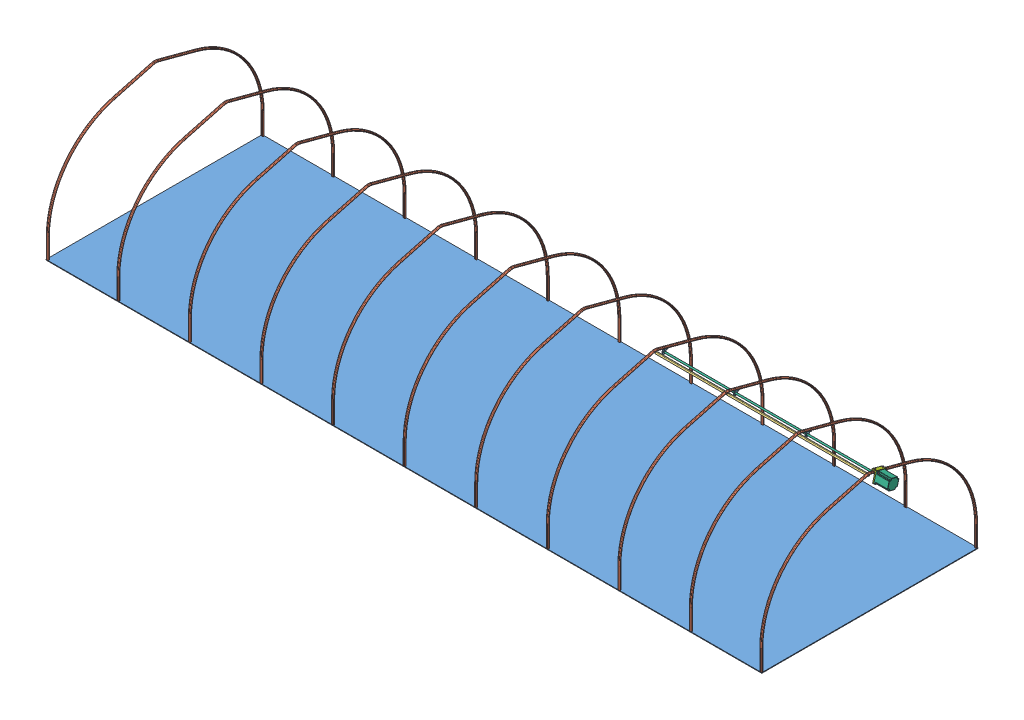
SolidWorks assembly Greenhouse_skrt, configuration Default. Lengths in mm.
Overall size (31100.8 5099.94 9207.5).
34 component instances, 7 part files, 68 mates.
Components (placement in the parent):
- Base 2-1: Base 2 [Default] at (10136.1399 15684.6804 24201.437) size (30480 25.4 9207.5)
- Arch-1: Arch [Default] at (25306.3916 15710.0804 28773.437) size (101.4 5043.5 9207.5)
- Arch-2: Arch [Default] at (22309.0899 15710.0801 28773.437) x (1 0.000015 0) z (0 0 1) size (101.4 5043.5 9207.5)
- Arch-3: Arch [Default] at (19261.0899 15710.0804 28773.437) size (101.4 5043.5 9207.5)
- Arch-8: Arch [Default] at (16213.0899 15710.0804 28773.437) size (101.4 5043.5 9207.5)
- Arch-10: Arch [Default] at (13165.0899 15710.0804 28773.437) size (101.4 5043.5 9207.5)
- Arch-11: Arch [Default] at (10117.0899 15710.0804 28773.437) size (101.4 5043.5 9207.5)
- Arch-12: Arch [Default] at (7069.0899 15710.0804 28773.437) size (101.4 5043.5 9207.5)
- Arch-13: Arch [Default] at (4021.0899 15710.0804 28773.437) size (101.4 5043.5 9207.5)
- Arch-14: Arch [Default] at (973.0899 15710.0804 28773.437) size (101.4 5043.5 9207.5)
- Arch-15: Arch [Default] at (-2074.9101 15710.0804 28773.437) size (101.4 5043.5 9207.5)
- Arch-16: Arch [Default] at (-5072.2119 15710.0804 28773.437) size (101.4 5043.5 9207.5)
- Beam-3: Beam [Default] at (25325.2675 20658.2948 24182.387) x (0 0 1) z (0.000015 -1 0) size (101.6 2997.2 63.5)
- heavy hex bolt_ai-9: heavy hex bolt_ai [HHBOLT 0.5000-20x0.5x0.5-N] at (25306.2173 20669.3537 24182.387) x (-0.000015 1 0) z (0 0 1) size (21.95 25.66 22.23)
- heavy hex bolt_ai-10: heavy hex bolt_ai [HHBOLT 0.5000-20x0.5x0.5-N] at (25306.2173 20669.3537 24220.487) x (-0.000015 1 0) z (0 0 1) size (21.95 25.66 22.23)
- heavy hex bolt_ai-12: heavy hex bolt_ai [HHBOLT 0.5000-20x0.5x0.5-N] at (25344.3899 20680.8325 24182.387) x (0 1 0) z (0 0 1) size (21.95 25.66 22.23)
- heavy hex bolt_ai-14: heavy hex bolt_ai [HHBOLT 0.5000-20x0.5x0.5-N] at (25344.3899 20680.8325 24220.487) x (0 1 0) z (0 0 1) size (21.95 25.66 22.23)
- shaft roller bearing-1: shaft roller bearing [Default] at (25310.4416 20588.1364 23874.3014) x (0 -0.257663 -0.966235) z (0 -0.966235 0.257663) size (240 68.1 205.28)
- shaft roller bearing-2: shaft roller bearing [Default] at (22313.0685 20588.1364 23874.3014) x (0.000004 -0.257663 -0.966235) z (0.000014 -0.966235 0.257663) size (240 68.1 205.28)
- shaft roller bearing-3: shaft roller bearing [Default] at (19295.1399 20549.487 23729.3662) x (0 0.257663 0.966235) z (0 -0.966235 0.257663) size (240 68.1 205.28)
- shaft roller bearing-4: shaft roller bearing [Default] at (16217.1399 20588.1364 23874.3014) x (0 -0.257663 -0.966235) z (0 -0.966235 0.257663) size (240 68.1 205.28)
- sketchy-stepper-1: sketchy-stepper [По умолчанию] at (25648.5904 20484.2662 23824.3793) x (0 0.257663 0.966235) z (0 0.966235 -0.257663) size (430 9724 465)
- Sketchy Holder-1: Sketchy Holder [Default] at (25426.9399 20493.0334 23822.1641) x (-1 0 0) z (0 -0.257663 -0.966235) size (177.8 448.06 429.77)
- heavy hex bolt_ai-17: heavy hex bolt_ai [HHBOLT 1.2500-12x1.25x1.25-N] at (25499.1903 20607.6263 23611.4055) x (-1 0 0) z (0 0.924225 0.381849) size (54 58.66 50.8)
- heavy hex bolt_ai-18: heavy hex bolt_ai [HHBOLT 1.2500-12x1.25x1.25-N] at (25499.1903 20697.2929 23947.6552) x (-1 0 0) z (0 0.924225 0.381849) size (54 58.66 50.8)
- heavy hex bolt_ai-19: heavy hex bolt_ai [HHBOLT 1.2500-12x1.25x1.25-N] at (25325.3399 20776.3479 23928.7763) x (0 -0.966235 0.257663) z (-0.257663 0.248963 0.93361) size (54 58.66 50.8)
- heavy hex bolt_ai-20: heavy hex bolt_ai [HHBOLT 1.2500-12x1.25x1.25-N] at (25325.3399 20685.6445 23588.6383) x (0 -0.966235 0.257663) z (-0.257663 0.248963 0.93361) size (54 58.66 50.8)
- heavy hex bolt_ai-21: heavy hex bolt_ai [HHBOLT 1.2500-12x1.25x1.25-N] at (25499.1903 20361.0432 24037.3218) x (-1 0 0) z (0 0.924225 0.381849) size (54 58.66 50.8)
- heavy hex bolt_ai-22: heavy hex bolt_ai [HHBOLT 1.2500-12x1.25x1.25-N] at (25404.6895 20271.3766 23701.0721) size (54 58.66 50.8)
- heavy hex bolt_ai-23: heavy hex bolt_ai [HHBOLT 1.2500-12x1.25x1.25-N] at (25480.9403 20271.3766 23701.0721) x (-1 0 0) z (0 0.924225 0.381849) size (54 58.66 50.8)
- heavy hex bolt_ai-24: heavy hex bolt_ai [HHBOLT 0.5000-13x1.25x1.25-N] at (22347.1173 20669.3105 24182.387) x (-0.000015 1 0) z (0 0 1) size (41 25.66 22.23)
- heavy hex bolt_ai-25: heavy hex bolt_ai [HHBOLT 0.5000-13x1.25x1.25-N] at (22347.1173 20669.3105 24220.487) x (-0.000015 1 0) z (0 0 1) size (41 25.66 22.23)
- Beam-4: Beam [Default] at (19330.8675 20658.9257 24220.487) x (0 0 -1) z (0.000015 -1 0) size (101.6 2997.2 63.5)
- Beam-5: Beam [Default] at (19280.1399 20658.3281 24182.387) x (0 0 1) z (0 -1 0) size (101.6 2997.2 63.5)
Mates (geometry in assembly coordinates):
- Concentric15: concentric anti-aligned: cylinder of Beam-3 through (22347.1174 20664.6013 24220.487) axis (-0.000015 1 0) radius 6.35; cylinder of Arch-2 through (22347.1169 20702.7783 24220.487) axis (0.000015 -1 0) radius 6.35
- Concentric16: concentric anti-aligned: cylinder of Beam-3 through (22347.1174 20664.6013 24182.387) axis (-0.000015 1 0) radius 6.35; cylinder of Arch-2 through (22347.1169 20702.7783 24182.387) axis (0.000015 -1 0) radius 6.35
- Concentric21: concentric anti-aligned: cylinder of Beam-3 through (25306.2174 20664.6445 24182.387) axis (-0.000015 1 0) radius 6.35; cylinder of heavy hex bolt_ai-9 through (25306.2173 20669.3537 24182.387) axis (0.000015 -1 0) radius 6.35
- Coincident40: coincident anti-aligned: plane of Beam-3 through (22328.0672 20678.5558 24182.387) normal (0.000015 -1 0); plane of heavy hex bolt_ai-9 through (25293.3856 20678.5991 24182.387) normal (-0.000015 1 0)
- Concentric22: concentric anti-aligned: cylinder of Beam-3 through (25306.2174 20664.6445 24220.487) axis (-0.000015 1 0) radius 6.35; cylinder of heavy hex bolt_ai-10 through (25306.2173 20669.3537 24220.487) axis (0.000015 -1 0) radius 6.35
- Coincident41: coincident anti-aligned: plane of Beam-3 through (22328.0672 20678.5558 24182.387) normal (0.000015 -1 0); plane of heavy hex bolt_ai-10 through (25293.3856 20678.5991 24220.487) normal (-0.000015 1 0)
- Coincident12: coincident anti-aligned: line of Base 2-1 through (-5103.8601 15710.0804 28805.187) axis (1 0 0); line of Arch-1 through (25344.4916 15710.0804 28805.187) axis (-1 0 0)
- Coincident13: coincident: line of Base 2-1 through (25376.1399 15710.0804 28805.187) axis (0 0 -1); point of Arch-1
- Coincident14: coincident: line of Base 2-1 through (25376.1399 15710.0804 28805.187) axis (0 0 -1); point of Arch-1
- Coincident15: coincident anti-aligned: line of Base 2-1 through (25376.1399 15710.0804 19597.687) axis (-1 0 0); line of Arch-1 through (25306.3916 15710.0804 19597.687) axis (1 0 0)
- Coincident16: coincident anti-aligned: line of Base 2-1 through (-5103.8601 15710.0804 28805.187) axis (1 0 0); line of Arch-16 through (-5034.1119 15710.0804 28805.187) axis (-1 0 0)
- Coincident17: coincident: line of Base 2-1 through (-5103.8601 15710.0804 19597.687) axis (0 0 1)
- Coincident18: coincident anti-aligned: line of Base 2-1 through (25376.1399 15710.0804 19597.687) axis (-1 0 0); line of Arch-16 through (-5072.2119 15710.0804 19597.687) axis (1 0 0)
- Coincident19: coincident: line of Base 2-1 through (-5103.8601 15710.0804 19597.687) axis (0 0 1); point of Arch-16
- Coincident23: coincident: line of Base 2-1 through (992.1399 15710.0804 28805.187) axis (0 0 -1)
- Coincident24: coincident anti-aligned: line of Base 2-1 through (-5103.8601 15710.0804 28805.187) axis (1 0 0); line of Arch-14 through (1011.1899 15710.0804 28805.187) axis (-1 0 0)
- Coincident25: coincident anti-aligned: line of Base 2-1 through (25376.1399 15710.0804 19597.687) axis (-1 0 0); line of Arch-14 through (973.0899 15710.0804 19597.687) axis (1 0 0)
- Perpendicular2: perpendicular: line of Base 2-1 through (-2055.8601 15710.0804 28805.187) axis (0 0 -1); line of Arch-15 through (-2074.9101 15710.0804 28773.437) axis (1 0 0)
- Coincident32: coincident: point of assembly; point of Base 2-1; moEndPointRef_w of Arch-2
- Coincident33: coincident: point of assembly; point of Base 2-1; moEndPointRef_w of Arch-3
- Coincident34: coincident: point of assembly; point of Base 2-1; moEndPointRef_w of Arch-8
- Coincident35: coincident: point of assembly; point of Base 2-1; moEndPointRef_w of Arch-10
- Coincident36: coincident: point of assembly; point of Base 2-1; moEndPointRef_w of Arch-11
- Coincident37: coincident: point of assembly; point of Base 2-1; moEndPointRef_w of Arch-12
- Coincident38: coincident: point of assembly; point of Base 2-1; moEndPointRef_w of Arch-13
- Concentric38: concentric aligned: cylinder of Arch-1 through (25344.4916 20583.237 23690.2079) axis (0 -0.966235 0.257663) radius 6.35; cylinder of shaft roller bearing-1 through (25344.4916 20570.9658 23693.4802) axis (0 -0.966235 0.257663) radius 6.35
- Concentric39: concentric aligned: cylinder of Arch-1 through (25306.3916 20583.237 23690.2079) axis (0 -0.966235 0.257663) radius 6.35; cylinder of shaft roller bearing-1 through (25306.3916 20570.9658 23693.4802) axis (0 -0.966235 0.257663) radius 6.35
- Concentric40: concentric aligned: cylinder of Arch-1 through (25344.4916 20636.9029 23891.4553) axis (0 -0.966235 0.257663) radius 6.35; cylinder of shaft roller bearing-1 through (25344.4916 20624.6317 23894.7276) axis (0 -0.966235 0.257663) radius 6.35
- Concentric41: concentric aligned: cylinder of Arch-1 through (25306.3916 20636.9029 23891.4553) axis (0 -0.966235 0.257663) radius 6.35; cylinder of shaft roller bearing-1 through (25306.3916 20624.6317 23894.7276) axis (0 -0.966235 0.257663) radius 6.35
- Coincident39: coincident anti-aligned: plane of Arch-1 through (25306.3916 20243.6172 22465.9231) normal (0 -0.966235 0.257663); plane of shaft roller bearing-1 through (25310.4416 20617.1235 23866.5715) normal (0 0.966235 -0.257663)
- Coincident43: coincident: point of assembly; point of Base 2-1; moEndPointRef_w of Arch-2
- Concentric47: concentric aligned: cylinder of Arch-2 through (22347.1178 20636.9032 23891.4553) axis (0.000014 -0.966235 0.257663) radius 6.35; cylinder of shaft roller bearing-2 through (22347.118 20624.6323 23894.7276) axis (0.000014 -0.966235 0.257663) radius 6.35
- Concentric48: concentric aligned: cylinder of Arch-2 through (22309.0186 20583.2367 23690.2079) axis (0.000014 -0.966235 0.257663) radius 6.35; cylinder of shaft roller bearing-2 through (22309.0188 20570.9657 23693.4801) axis (0.000014 -0.966235 0.257663) radius 6.35
- Coincident44: coincident: point of assembly; point of Base 2-1; moEndPointRef_w of Arch-3
- Concentric50: concentric aligned: cylinder of Arch-3 through (19299.1899 20636.9029 23891.4553) axis (0 -0.966235 0.257663) radius 6.35; cylinder of shaft roller bearing-3 through (19299.1899 20624.6317 23894.7276) axis (0 -0.966235 0.257663) radius 6.35
- Concentric51: concentric aligned: cylinder of Arch-3 through (19261.0899 20583.237 23690.2079) axis (0 -0.966235 0.257663) radius 6.35; cylinder of shaft roller bearing-3 through (19261.0899 20570.9658 23693.4802) axis (0 -0.966235 0.257663) radius 6.35
- Coincident45: coincident: point of assembly; point of Base 2-1; moEndPointRef_w of Arch-8
- Concentric52: concentric aligned: cylinder of Arch-8 through (16251.1899 20636.9029 23891.4553) axis (0 -0.966235 0.257663) radius 6.35; cylinder of shaft roller bearing-4 through (16251.1899 20624.6317 23894.7276) axis (0 -0.966235 0.257663) radius 6.35
- Concentric53: concentric aligned: cylinder of Arch-8 through (16213.0899 20583.237 23690.2079) axis (0 -0.966235 0.257663) radius 6.35; cylinder of shaft roller bearing-4 through (16213.0899 20570.9658 23693.4802) axis (0 -0.966235 0.257663) radius 6.35
- Concentric55: concentric aligned: cylinder of shaft roller bearing-1 through (25310.4416 20484.2662 23824.3793) axis (1 0 0) radius 32; cylinder of sketchy-stepper-1 through (16272.9399 20484.2662 23824.3793) axis (1 0 0) radius 32.004
- Coincident53: coincident anti-aligned: plane of Arch-1 through (25344.4916 20304.9731 22449.5615) normal (0 0.966235 -0.257663); plane of Sketchy Holder-1 through (25249.1399 20603.8176 23570.2285) normal (0 -0.966235 0.257663)
- Coincident54: coincident: line of Arch-1 through (25376.1399 20276.7494 22457.0878) axis (0 0.257663 0.966235); plane of Sketchy Holder-1 through (25376.1399 20493.0334 23822.1641) normal (-1 0 0)
- Parallel19: parallel aligned: line of sketchy-stepper-1 through (25426.9399 20643.1194 23585.3815) axis (0 0.257663 0.966235); line of Sketchy Holder-1 through (25426.9399 20657.4018 23569.0832) axis (0 0.257663 0.966235)
- Coincident61: coincident anti-aligned: line of sketchy-stepper-1 through (25426.9399 20723.3169 23983.1483) axis (0 -0.966235 0.257663); line of Sketchy Holder-1 through (25426.9399 20344.2085 24084.2438) axis (0 0.966235 -0.257663)
- Concentric74: concentric anti-aligned: cylinder of sketchy-stepper-1 through (25426.9399 20607.6263 23611.4055) axis (-1 0 0) radius 16.25; cylinder of heavy hex bolt_ai-17 through (25499.1903 20607.6263 23611.4055) axis (1 0 0) radius 15.875
- Coincident63: coincident anti-aligned: plane of sketchy-stepper-1 through (25476.9399 20251.7942 23689.7349) normal (1 0 0); plane of heavy hex bolt_ai-17 through (25476.9399 20560.6757 23592.0075) normal (-1 0 0)
- Concentric75: concentric anti-aligned: cylinder of sketchy-stepper-1 through (25426.9399 20697.2929 23947.6552) axis (-1 0 0) radius 16.25; cylinder of heavy hex bolt_ai-18 through (25499.1903 20697.2929 23947.6552) axis (1 0 0) radius 15.875
- Coincident64: coincident anti-aligned: plane of sketchy-stepper-1 through (25476.9399 20251.7942 23689.7349) normal (1 0 0); plane of heavy hex bolt_ai-18 through (25476.9399 20650.3423 23928.2573) normal (-1 0 0)
- Concentric76: concentric aligned: cylinder of Sketchy Holder-1 through (25325.3399 20681.2217 23954.1433) axis (0 0.966235 -0.257663) radius 16.256; cylinder of heavy hex bolt_ai-19 through (25325.3399 20776.3479 23928.7763) axis (0 0.966235 -0.257663) radius 15.875
- Coincident65: coincident anti-aligned: plane of Sketchy Holder-1 through (25376.1399 20709.4971 23764.4404) normal (0 0.966235 -0.257663); plane of heavy hex bolt_ai-19 through (25338.4291 20742.2015 23887.082) normal (0 -0.966235 0.257663)
- Concentric77: concentric aligned: cylinder of Sketchy Holder-1 through (25325.3399 20590.5182 23614.0053) axis (0 0.966235 -0.257663) radius 16.256; cylinder of heavy hex bolt_ai-20 through (25325.3399 20685.6445 23588.6383) axis (0 0.966235 -0.257663) radius 15.875
- Coincident66: coincident anti-aligned: plane of Sketchy Holder-1 through (25376.1399 20709.4971 23764.4404) normal (0 0.966235 -0.257663); plane of heavy hex bolt_ai-20 through (25338.4291 20651.498 23546.9441) normal (0 -0.966235 0.257663)
- Concentric78: concentric anti-aligned: cylinder of sketchy-stepper-1 through (25426.9399 20361.0432 24037.3218) axis (-1 0 0) radius 16.25; cylinder of heavy hex bolt_ai-21 through (25499.1903 20361.0432 24037.3218) axis (1 0 0) radius 15.875
- Coincident67: coincident anti-aligned: plane of sketchy-stepper-1 through (25476.9399 20251.7942 23689.7349) normal (1 0 0); plane of heavy hex bolt_ai-21 through (25476.9399 20314.0926 24017.9239) normal (-1 0 0)
- Concentric79: concentric aligned: cylinder of sketchy-stepper-1 through (25426.9399 20271.3766 23701.0721) axis (-1 0 0) radius 16.25; cylinder of heavy hex bolt_ai-22 through (25404.6895 20271.3766 23701.0721) axis (-1 0 0) radius 15.875
- Coincident68: coincident anti-aligned: plane of sketchy-stepper-1 through (25426.9399 20251.7942 23689.7349) normal (-1 0 0); plane of heavy hex bolt_ai-22 through (25426.9399 20271.3766 23650.2721) normal (1 0 0)
- Concentric80: concentric aligned: cone of heavy hex bolt_ai-22 through (25458.6899 20271.3766 23701.0721) axis (1 0 0); cylinder of heavy hex bolt_ai-23 through (25480.9403 20271.3766 23701.0721) axis (1 0 0) radius 15.875
- Coincident69: coincident anti-aligned: plane of heavy hex bolt_ai-22 through (25458.6899 20271.3766 23701.0721) normal (1 0 0); plane of heavy hex bolt_ai-23 through (25458.6899 20224.426 23681.6741) normal (-1 0 0)
- Concentric81: concentric anti-aligned: cylinder of Beam-3 through (22347.1174 20664.6013 24182.387) axis (-0.000015 1 0) radius 6.35; cylinder of heavy hex bolt_ai-24 through (22347.1173 20669.3105 24182.387) axis (0.000015 -1 0) radius 6.35
- Coincident70: coincident anti-aligned: plane of Beam-3 through (22328.0672 20678.5558 24182.387) normal (0.000015 -1 0); plane of heavy hex bolt_ai-24 through (22347.1172 20678.5561 24160.162) normal (-0.000015 1 0)
- Concentric82: concentric anti-aligned: cylinder of Beam-3 through (22347.1174 20664.6013 24220.487) axis (-0.000015 1 0) radius 6.35; cylinder of heavy hex bolt_ai-25 through (22347.1173 20669.3105 24220.487) axis (0.000015 -1 0) radius 6.35
- Coincident71: coincident anti-aligned: plane of Beam-3 through (22328.0672 20678.5558 24182.387) normal (0.000015 -1 0); plane of heavy hex bolt_ai-25 through (22347.1172 20678.5561 24198.262) normal (-0.000015 1 0)
- Concentric84: concentric anti-aligned: cylinder of Arch-2 through (22309.0169 20702.7778 24220.487) axis (0.000015 -1 0) radius 6.35; cylinder of Beam-4 through (22309.0174 20665.3193 24220.487) axis (-0.000015 1 0) radius 6.35
- Concentric85: concentric anti-aligned: cylinder of Arch-2 through (22309.0169 20702.7778 24182.387) axis (0.000015 -1 0) radius 6.35; cylinder of Beam-4 through (22309.0174 20665.3193 24182.387) axis (-0.000015 1 0) radius 6.35
- Tangent1: tangent: curve of Arch-2; circle of Beam-4
- Concentric86: concentric anti-aligned: cylinder of Arch-3 through (19261.0899 20702.7781 24182.387) axis (0 -1 0) radius 6.35; cylinder of Beam-5 through (19261.0899 20627.8747 24182.387) axis (0 1 0) radius 6.35
- Concentric87: concentric anti-aligned: cylinder of Arch-3 through (19261.0899 20702.7781 24220.487) axis (0 -1 0) radius 6.35; cylinder of Beam-5 through (19261.0899 20627.8747 24220.487) axis (0 1 0) radius 6.35
- Coincident72: coincident anti-aligned: circle of Arch-3; circle of Beam-5
